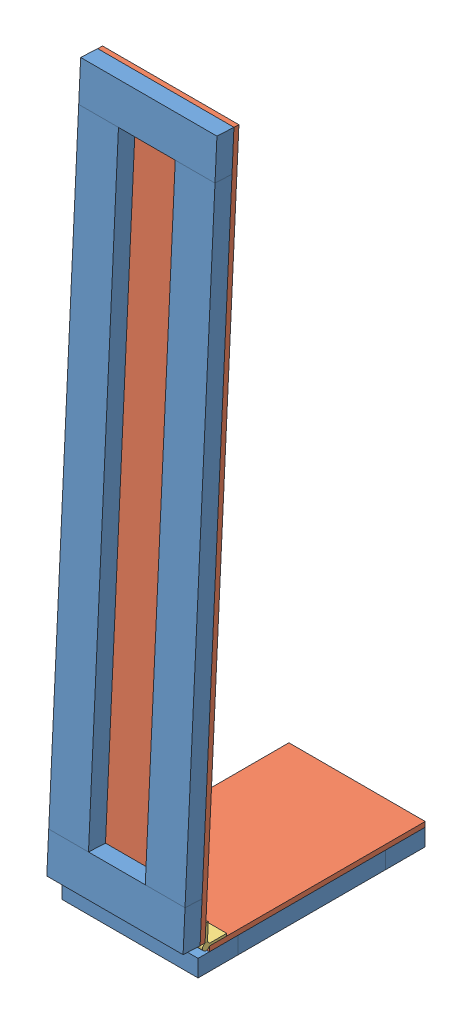
SolidWorks assembly PlotterSupport, configuration Default. Lengths in mm.
Overall size (304.8 1609.43 541.53).
14 component instances, 3 part files, 40 mates.
Components (placement in the parent):
- 2x4_Plotter-1: 2x4_Plotter [PlotterWidth] at (215.9 150.676 537.183) x (1 0 0) z (0 0.998805 -0.048876) size (88.9 38.1 1371.6)
- 2x4_Plotter-2: 2x4_Plotter [PlotterWidth] at (0 150.676 537.183) x (1 0 0) z (0 0.998805 -0.048876) size (88.9 38.1 1371.6)
- 2x4_Plotter-3: 2x4_Plotter [PlotterDepth] at (304.8 1520.6367 470.144) x (0 0.998805 -0.048876) z (-1 0 0) size (88.9 38.1 304.8)
- 2x4_Plotter-4: 2x4_Plotter [PlotterDepth] at (0 150.676 537.183) x (0 -0.998805 0.048876) z (1 0 0) size (88.9 38.1 304.8)
- 2x4_Plotter-5: 2x4_Plotter [PlotterDepth] at (0 0 508) x (0 0 -1) z (1 0 0) size (88.9 38.1 304.8)
- 2x4_Plotter-6: 2x4_Plotter [PlotterBase] at (215.9 0 88.9) size (88.9 38.1 330.2)
- 2x4_Plotter-7: 2x4_Plotter [PlotterBase] at (0 0 88.9) size (88.9 38.1 330.2)
- Plywood_Plotter-1: Plywood_Plotter [PlotterDepth-X-PlotterWidth] at (0 59.4769 492.3744) x (1 0 0) z (0 0.048876 0.998805) size (304.8 1549.4 11.11)
- Plywood_Plotter-2: Plywood_Plotter [PlotterDepth-X-PlotterBase] at (0 49.2125 0) x (1 0 0) z (0 -1 0) size (304.8 482.6 11.11)
- Hinge-3: Hinge [Reverse] at (304.8 51.8795 490.076) x (0 0.998805 -0.048876) z (-1 0 0) size (53.98 15.88 101.6)
- Hinge-4: Hinge [Reverse] at (101.6 51.8795 490.076) x (0 0.998805 -0.048876) z (-1 0 0) size (53.98 15.88 101.6)
- Hinge-5: Hinge [Default] at (203.2 51.8795 490.076) x (0 0 -1) z (1 0 0) size (53.98 15.88 101.6)
- Hinge-6: Hinge [Default] at (0 51.8795 490.076) x (0 0 -1) z (1 0 0) size (53.98 15.88 101.6)
- 2x4_Plotter-9: 2x4_Plotter [PlotterDepth] at (0 0 88.9) x (0 0 -1) z (1 0 0) size (88.9 38.1 304.8)
Mates (geometry in assembly coordinates):
- Coincident32: coincident anti-aligned: plane of 2x4_Plotter-2 through (0 150.676 537.183) normal (0 -0.998805 0.048876); plane of 2x4_Plotter-4 through (304.8 150.676 537.183) normal (0 0.998805 -0.048876)
- Coincident33: coincident aligned: plane of 2x4_Plotter-2 through (0 1520.6367 470.144) normal (-1 0 0); plane of 2x4_Plotter-4 through (0 150.676 537.183) normal (-1 0 0)
- Coincident34: coincident aligned: plane of 2x4_Plotter-1 through (304.8 1520.6367 470.144) normal (1 0 0); plane of 2x4_Plotter-4 through (304.8 150.676 537.183) normal (1 0 0)
- Coincident35: coincident aligned: plane of 2x4_Plotter-2 through (0 1518.7745 432.0895) normal (0 -0.048876 -0.998805); plane of 2x4_Plotter-4 through (304.8 148.8138 499.1285) normal (0 -0.048876 -0.998805)
- Coincident36: coincident aligned: plane of 2x4_Plotter-1 through (215.9 1518.7745 432.0895) normal (0 -0.048876 -0.998805); plane of 2x4_Plotter-4 through (304.8 148.8138 499.1285) normal (0 -0.048876 -0.998805)
- Coincident37: coincident aligned: plane of 2x4_Plotter-1 through (304.8 1520.6367 470.144) normal (1 0 0); plane of 2x4_Plotter-3 through (304.8 1520.6367 470.144) normal (1 0 0)
- Coincident38: coincident anti-aligned: plane of 2x4_Plotter-1 through (215.9 1520.6367 470.144) normal (0 0.998805 -0.048876); plane of 2x4_Plotter-3 through (0 1520.6367 470.144) normal (0 -0.998805 0.048876)
- Coincident39: coincident aligned: plane of 2x4_Plotter-1 through (215.9 1518.7745 432.0895) normal (0 -0.048876 -0.998805); plane of 2x4_Plotter-3 through (0 1518.7745 432.0895) normal (0 -0.048876 -0.998805)
- Coincident62: coincident aligned: plane of 2x4_Plotter-7 through (0 0 419.1) normal (-1 0 0); plane of 2x4_Plotter-5 through (0 0 508) normal (-1 0 0)
- Coincident66: coincident anti-aligned: plane of 2x4_Plotter-5 through (304.8 0 419.1) normal (0 0 -1); plane of 2x4_Plotter-7 through (0 0 419.1) normal (0 0 1)
- Coincident69: coincident anti-aligned: plane of 2x4_Plotter-2 through (0 1518.7745 432.0895) normal (0 -0.048876 -0.998805); plane of Plywood_Plotter-1 through (0 60.0201 503.4737) normal (0 0.048876 0.998805)
- Coincident70: coincident aligned: plane of 2x4_Plotter-2 through (0 1520.6367 470.144) normal (-1 0 0); plane of Plywood_Plotter-1 through (0 60.0201 503.4737) normal (-1 0 0)
- Coincident71: coincident aligned: plane of 2x4_Plotter-4 through (304.8 61.8823 541.5281) normal (0 -0.998805 0.048876); plane of Plywood_Plotter-1 through (0 60.0201 503.4737) normal (0 -0.998805 0.048876)
- Coincident73: coincident aligned: plane of 2x4_Plotter-7 through (0 0 419.1) normal (-1 0 0); plane of Plywood_Plotter-2 through (0 38.1 0) normal (-1 0 0)
- Coincident75: coincident aligned: line of Plywood_Plotter-1 through (0 59.4769 492.3744) axis (1 0 0); line of Hinge-3 through (284.48 59.4769 492.3744) axis (1 0 0)
- Coincident77: coincident anti-aligned: plane of Plywood_Plotter-1 through (0 59.4769 492.3744) normal (0 -0.048876 -0.998805); plane of Hinge-3 through (203.2 52.0099 492.7398) normal (0 0.048876 0.998805)
- Coincident78: coincident aligned: plane of Plywood_Plotter-1 through (304.8 60.0201 503.4737) normal (1 0 0); plane of Hinge-3 through (304.8 51.8795 490.076) normal (1 0 0)
- Coincident79: coincident aligned: line of Plywood_Plotter-1 through (0 59.4769 492.3744) axis (1 0 0); line of Hinge-4 through (0 59.4769 492.3744) axis (1 0 0)
- Coincident80: coincident anti-aligned: plane of Plywood_Plotter-1 through (0 59.4769 492.3744) normal (0 -0.048876 -0.998805); plane of Hinge-4 through (0 52.0099 492.7398) normal (0 0.048876 0.998805)
- Coincident81: coincident aligned: plane of Plywood_Plotter-1 through (0 60.0201 503.4737) normal (-1 0 0); plane of Hinge-4 through (0 51.8795 490.076) normal (-1 0 0)
- Coincident82: coincident anti-aligned: circle of Hinge-3; circle of Hinge-5
- Coincident83: coincident aligned: plane of Hinge-3 through (304.8 51.8795 490.076) normal (1 0 0); plane of Hinge-5 through (304.8 51.8795 490.076) normal (1 0 0)
- Coincident85: coincident anti-aligned: circle of Hinge-4; circle of Hinge-6
- Coincident86: coincident aligned: plane of Hinge-4 through (0 51.8795 490.076) normal (-1 0 0); plane of Hinge-6 through (0 51.8795 490.076) normal (-1 0 0)
- Coincident87: coincident anti-aligned: plane of Plywood_Plotter-2 through (0 49.2125 0) normal (0 1 0); plane of Hinge-6 through (101.6 49.2125 490.076) normal (0 -1 0)
- Coincident88: coincident anti-aligned: plane of Plywood_Plotter-2 through (0 49.2125 0) normal (0 1 0); plane of Hinge-5 through (304.8 49.2125 490.076) normal (0 -1 0)
- Coincident89: coincident aligned: plane of Plywood_Plotter-2 through (0 38.1 0) normal (-1 0 0); plane of Hinge-6 through (0 51.8795 490.076) normal (-1 0 0)
- Coincident90: coincident aligned: line of Plywood_Plotter-2 through (304.8 49.2125 482.6) axis (-1 0 0); line of Hinge-6 through (20.32 49.2125 482.6) axis (-1 0 0)
- Coincident91: coincident anti-aligned: plane of 2x4_Plotter-2 through (0 1520.6367 470.144) normal (0 0.998805 -0.048876); plane of 2x4_Plotter-3 through (0 1520.6367 470.144) normal (0 -0.998805 0.048876)
- Coincident92: coincident anti-aligned: plane of 2x4_Plotter-5 through (304.8 0 508) normal (0 -1 0); plane of assembly through (0 0 0) normal (0 1 0)
- Coincident94: coincident anti-aligned: plane of 2x4_Plotter-7 through (0 0 419.1) normal (-1 0 0); plane of assembly through (0 0 0) normal (1 0 0)
- Coincident95: coincident anti-aligned: plane of 2x4_Plotter-7 through (0 0 88.9) normal (0 0 -1); plane of 2x4_Plotter-9 through (304.8 0 88.9) normal (0 0 1)
- Coincident96: coincident aligned: plane of 2x4_Plotter-7 through (0 0 419.1) normal (-1 0 0); plane of 2x4_Plotter-9 through (0 0 88.9) normal (-1 0 0)
- Coincident97: coincident anti-aligned: plane of Plywood_Plotter-2 through (0 38.1 0) normal (0 -1 0); plane of 2x4_Plotter-9 through (304.8 38.1 88.9) normal (0 1 0)
- Coincident98: coincident anti-aligned: plane of 2x4_Plotter-7 through (0 38.1 419.1) normal (0 1 0); plane of Plywood_Plotter-2 through (0 38.1 0) normal (0 -1 0)
- Coincident99: coincident anti-aligned: plane of 2x4_Plotter-6 through (215.9 0 88.9) normal (0 0 -1); plane of 2x4_Plotter-9 through (304.8 0 88.9) normal (0 0 1)
- Coincident100: coincident anti-aligned: plane of 2x4_Plotter-6 through (215.9 38.1 419.1) normal (0 1 0); plane of Plywood_Plotter-2 through (0 38.1 0) normal (0 -1 0)
- Coincident101: coincident anti-aligned: plane of 2x4_Plotter-5 through (304.8 38.1 508) normal (0 1 0); plane of Plywood_Plotter-2 through (0 38.1 0) normal (0 -1 0)
- Coincident102: coincident aligned: plane of Plywood_Plotter-2 through (0 38.1 0) normal (0 0 -1); plane of 2x4_Plotter-9 through (304.8 0 0) normal (0 0 -1)
- Coincident103: coincident anti-aligned: plane of 2x4_Plotter-9 through (304.8 0 0) normal (0 0 -1); plane of assembly through (0 0 0) normal (0 0 1)
